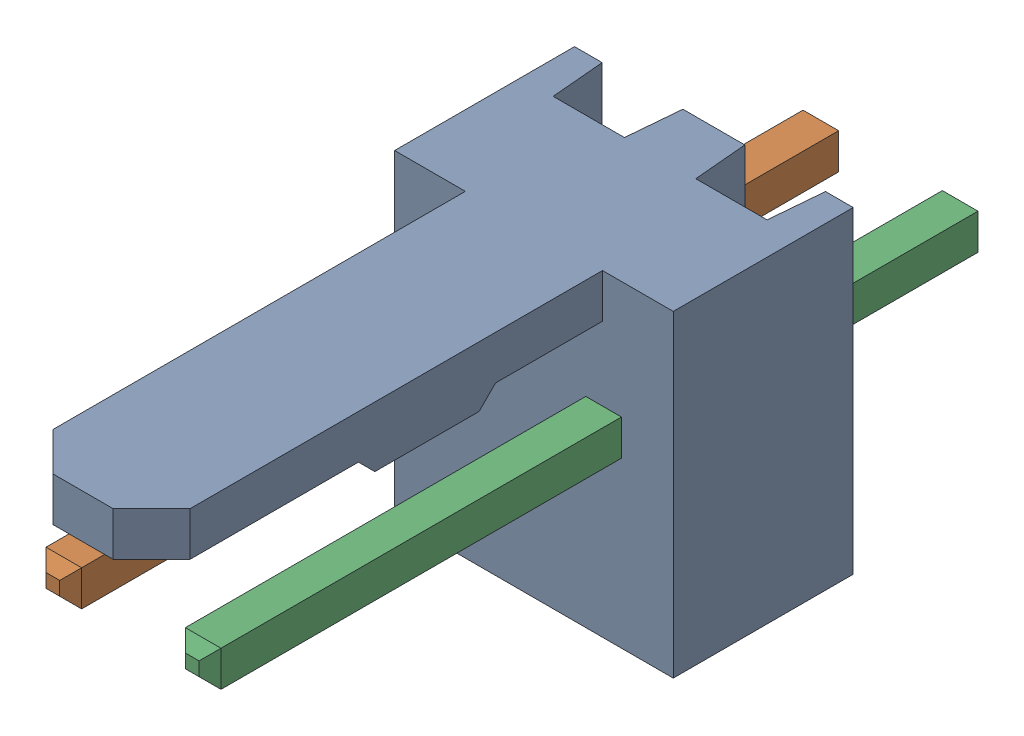
SolidWorks assembly Molex PCB 2 pin v2 (7), configuration Default. Lengths in mm.
Overall size (5.08 5.79 14.92).
3 component instances, 2 part files, 0 mates.
Components (placement in the parent):
- BASE9710016-1: BASE9710016 [Default] at (18.04 2.895 -8.22) size (5.08 5.79 11.5)
- PINO9710016-1: PINO9710016 [Default] at (16.77 3.325 -0.72) size (0.65 0.65 14.2)
- PINO9710016-2: PINO9710016 [Default] at (19.31 3.325 -0.72) size (0.65 0.65 14.2)
